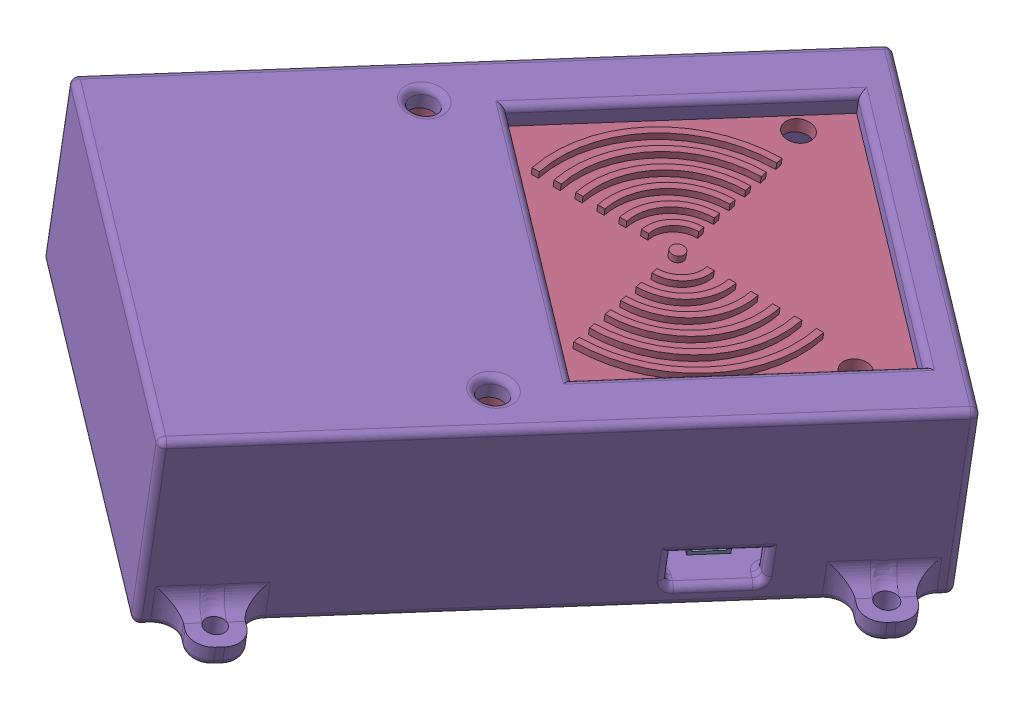
SolidWorks assembly Montagem_do_equipamento, configuration Valor predeterminado. Lengths in mm.
Overall size (117.17 46 119.15).
5 component instances, 5 part files, 10 mates.
Components (placement in the parent):
- esp32-1: esp32 [Valor predeterminado] at (-83.3826 63.2055 -95.1491) x (0.805375 -0.147546 0.574109) z (0.568773 -0.080413 -0.818555) size (52 10 29)
- BOTAO_modelo_3D-1: BOTAO_modelo_3D [Valor predeterminado] at (-128.611 76.875 -87.8923) x (-0.591034 -0.273868 0.758733) z (0.045283 -0.950382 -0.307771) size (17 25.5 17)
- LED_RGB_modelo_3D-1: LED_RGB_modelo_3D [Valor predeterminado] at (-103.1696 72.9612 -111.5295) x (0.375131 -0.623042 -0.686364) z (0.458964 0.768146 -0.446434) size (6 17.6 6)
- RFID_modelo_3D-1: RFID_modelo_3D [Valor predeterminado] at (-43.9619 70.0488 -60.0165) x (0.805375 -0.147546 0.574109) z (-0.568773 0.080413 0.818555) size (55 12 85)
- CASE_EQUIPAMENTO_modelo_3D-1: CASE_EQUIPAMENTO_modelo_3D [Valor predeterminado] at (-76.9722 53.0099 -96.1696) x (0.568773 -0.080413 -0.818555) z (0.16694 0.985781 0.019157) size (93 74 28)
Mates (geometry in assembly coordinates):
- Coincidente1: coincident anti-aligned: plane of esp32-1 through (-71.4619 58.736 -73.44) normal (-0.16694 -0.985781 -0.019157); plane of CASE_EQUIPAMENTO_modelo_3D-1 through (-71.4619 58.736 -73.44) normal (0.16694 0.985781 0.019157)
- Coincidente2: coincident anti-aligned: plane of LED_RGB_modelo_3D-1 through (-104.3752 73.1821 -112.389) normal (-0.805375 0.147546 -0.574109); plane of CASE_EQUIPAMENTO_modelo_3D-1 through (-104.6431 58.0792 -115.8947) normal (0.805375 -0.147546 0.574109)
- Concêntrico3: concentric anti-aligned: cylinder of LED_RGB_modelo_3D-1 through (-104.0022 73.1138 -112.1231) axis (0.805375 -0.147546 0.574109) radius 2.5; cylinder of CASE_EQUIPAMENTO_modelo_3D-1 through (-104.3752 73.1821 -112.389) axis (-0.805375 0.147546 -0.574109) radius 2.65
- Coincidente3: coincident anti-aligned: plane of BOTAO_modelo_3D-1 through (-126.1949 76.4324 -86.17) normal (0.805375 -0.147546 0.574109); plane of CASE_EQUIPAMENTO_modelo_3D-1 through (-145.7648 67.0222 -61.1352) normal (-0.805375 0.147546 -0.574109)
- Tangente1: tangent: curve of BOTAO_modelo_3D-1; cylinder of CASE_EQUIPAMENTO_modelo_3D-1 through (-128.0288 74.5075 -78.8666) axis (-0.805375 0.147546 -0.574109) radius 6.75
- Concêntrico4: concentric anti-aligned: cylinder of esp32-1 through (-110.1199 65.8182 -100.9973) axis (0.16694 0.985781 0.019157) radius 1; cylinder of CASE_EQUIPAMENTO_modelo_3D-1 through (-110.1199 65.8182 -100.9973) axis (-0.16694 -0.985781 -0.019157) radius 0.75
- Concêntrico5: concentric anti-aligned: cylinder of esp32-1 through (-95.9006 63.8078 -121.4611) axis (0.16694 0.985781 0.019157) radius 1; cylinder of CASE_EQUIPAMENTO_modelo_3D-1 through (-95.9006 63.8078 -121.4611) axis (-0.16694 -0.985781 -0.019157) radius 0.75
- Concêntrico6: concentric aligned: cylinder of RFID_modelo_3D-1 through (-115.1759 81.6569 -88.9631) axis (0.16694 0.985781 0.019157) radius 2; cylinder of CASE_EQUIPAMENTO_modelo_3D-1 through (-114.6751 84.6142 -88.9056) axis (0.16694 0.985781 0.019157) radius 2
- Concêntrico7: concentric aligned: cylinder of RFID_modelo_3D-1 through (-77.3233 74.7222 -61.98) axis (0.16694 0.985781 0.019157) radius 2; cylinder of CASE_EQUIPAMENTO_modelo_3D-1 through (-76.8225 77.6796 -61.9225) axis (0.16694 0.985781 0.019157) radius 2
- Coincidente4: coincident anti-aligned: plane of RFID_modelo_3D-1 through (-43.628 72.0204 -59.9782) normal (0.16694 0.985781 0.019157); plane of CASE_EQUIPAMENTO_modelo_3D-1 through (-72.7987 77.6544 -95.6906) normal (-0.16694 -0.985781 -0.019157)
